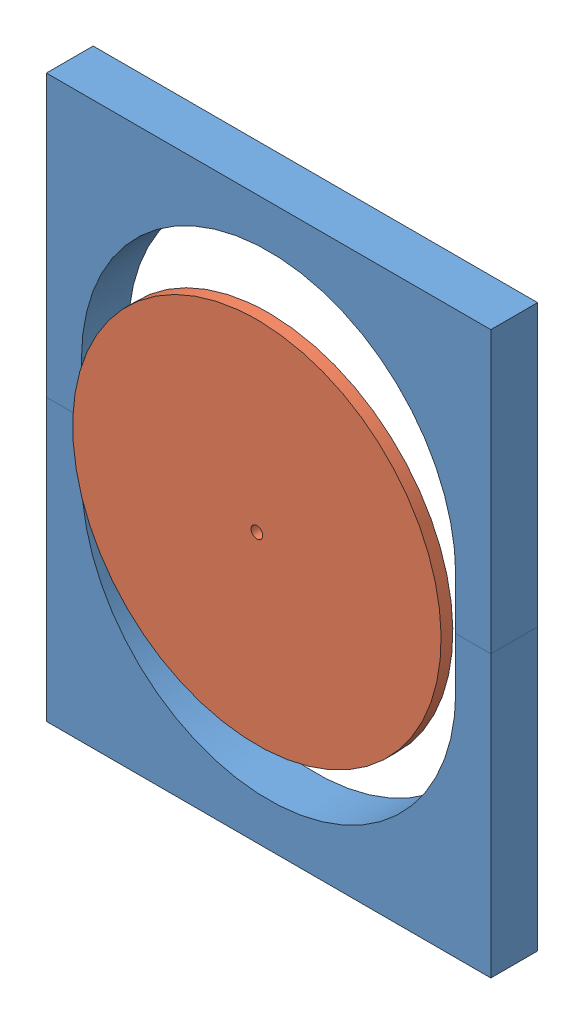
SolidWorks assembly Foam Layout, configuration Default. Lengths in mm.
Overall size (965.1 1219.2 127).
3 component instances, 2 part files, 6 mates.
Components (placement in the parent):
- Support Foam-1: Support Foam [Default] at (-409.1432 -167.1033 329.4268) size (965.1 609.6 101.6)
- Support Foam-3: Support Foam [Default] at (-409.1432 1052.0967 431.0268) x (1 0 0) z (0 0 -1) size (965.1 609.6 101.6)
- Shroud Foam Disk-1: Shroud Foam Disk [Default] at (73.4068 442.4967 456.4268) x (0.998874 0.047433 0) z (-0.047433 0.998874 0) size (800 25.4 800)
Mates (geometry in assembly coordinates):
- Coincident3: coincident anti-aligned: plane of Support Foam-1 through (-409.1432 442.4967 431.0268) normal (0 1 0); plane of Support Foam-3 through (479.7568 442.4967 329.4268) normal (0 -1 0)
- Coincident4: coincident aligned: plane of Support Foam-1 through (555.9568 -167.1033 431.0268) normal (1 0 0); plane of Support Foam-3 through (555.9568 1052.0967 329.4268) normal (1 0 0)
- Coincident5: coincident aligned: plane of Support Foam-1 through (73.4068 332.8967 431.0268) normal (0 0 1); plane of Support Foam-3 through (73.4068 552.0967 431.0268) normal (0 0 1)
- Coincident6: coincident anti-aligned: plane of Support Foam-3 through (73.4068 552.0967 431.0268) normal (0 0 1); plane of Shroud Foam Disk-1 through (73.4068 438.9431 431.0268) normal (0 0 -1)
- Distance1: distance = 482.55 mm: moEndPointRef_w of Shroud Foam Disk-1; plane of Support Foam-1 through (-409.1432 -167.1033 431.0268) normal (-1 0 0)
- Distance2: distance = 609.6 mm: moEndPointRef_w of Shroud Foam Disk-1; plane of Support Foam-3 through (-409.1432 1052.0967 329.4268) normal (0 1 0)
